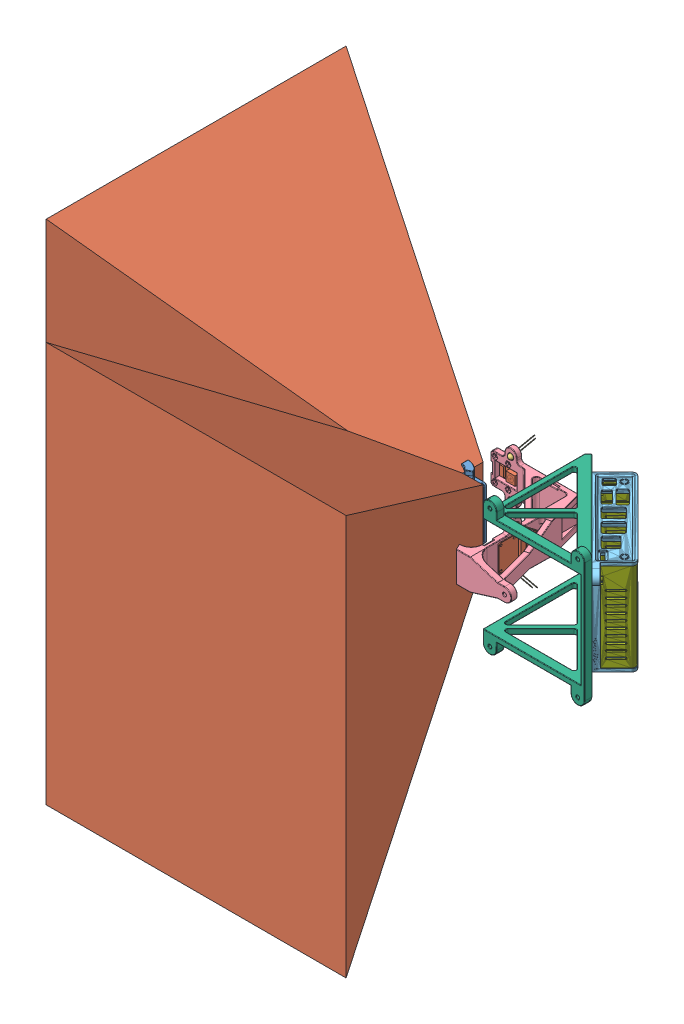
SolidWorks assembly Camera Mount Reference Assembly, configuration Default. Lengths in mm.
Overall size (267.17 129.73 171.67).
12 component instances, 7 part files, 32 mates.
Components (placement in the parent):
- Water Tunnel-1: Water Tunnel [Default] at origin size (93.6 95.16 58.74)
- Arducam IMX219AF-1: Arducam IMX219AF [Default] at (60.2 0 20.3) x (0 1 0) z (1 0 0) size (382.24 286.19 308.6)
- Arducam IMX219AF-2: Arducam IMX219AF [Default] at (-5.3 0 -45.2) x (0 -1 0) z (0 0 -1) size (382.24 286.19 308.6)
- 5mm White LED-1: 5mm White LED [Default] at (0 -19.4708 -46.6949) x (1 0 0) z (0 -0.978428 0.206589) size (5.4 26.8 5.4)
- 5mm White LED-2: 5mm White LED [Default] at (0 19.4708 -46.6949) x (1 0 0) z (0 -0.978428 -0.206589) size (5.4 26.8 5.4)
- 5mm White LED-3: 5mm White LED [Default] at (61.74 -19.5245 15) x (0 0 1) z (-0.22637 -0.974041 0) size (5.4 26.8 5.4)
- 5mm White LED-4: 5mm White LED [Default] at (61.74 19.5245 15) x (0 0 1) z (0.22637 -0.974041 0) size (5.4 26.8 5.4)
- Camera Mount-1: Camera Mount [Default] at (-5.3 0 -45.2) x (0 1 0) z (0 0 1) size (50.45 118.63 103.89)
- Jetson Mount Reference Assembly-1: Jetson Mount Reference Assembly [Default] at (34.246 111.7133 -83.3741) x (0.707107 0 0.707107) z (0.707107 0 -0.707107) size (136.69 127.15 104.23)
  - NanoBoxABSforB01_Bottom-1: NanoBoxABSforB01_Bottom [Default] at origin size (131.92 90.31 31)
  - Jetson Mount-1: Jetson Mount [Default] x (-1 0 0) z (0 0 -1) size (136.69 127.15 73.23)
  - NanoBoxABSforB01_Top-1: NanoBoxABSforB01_Top [Default] at (250 -0.2998 30.7) x (-1 0 0) z (0 0 -1) size (105.92 84.31 25)
Mates (geometry in assembly coordinates):
- Coincident1: coordinate: point of Water Tunnel-1
- Coincident2: coincident anti-aligned: plane of Water Tunnel-1 through (5 -15 20) normal (-1 0 0); plane of Arducam IMX219AF-1 through (5 0 20.3) normal (1 0 0)
- Coincident5: coincident aligned: plane of Water Tunnel-1 through (0 0 15) normal (0 0 1); plane of Arducam IMX219AF-1 through (60.2 0 15) normal (0 0 1)
- Coincident6: coincident aligned: plane of Water Tunnel-1 through (0 0 0) normal (0 1 0); plane of Arducam IMX219AF-1 through (60.2 0 20.3) normal (0 1 0)
- Coincident7: coincident: line of Water Tunnel-1 through (-5 -15 10) axis (0 1 0); plane of Arducam IMX219AF-2 through (-5.3 0 10) normal (0 0 -1)
- Coincident8: coincident: line of Water Tunnel-1 through (5 15 10) axis (0 -1 0); plane of Arducam IMX219AF-2 through (-5.3 0 10) normal (0 0 -1)
- Coincident9: coincident anti-aligned: plane of Water Tunnel-1 through (0 0 0) normal (1 0 0); plane of Arducam IMX219AF-2 through (0 0 -45.2) normal (-1 0 0)
- Coincident10: coincident anti-aligned: plane of Water Tunnel-1 through (0 0 0) normal (0 1 0); plane of Arducam IMX219AF-2 through (-5.3 0 -45.2) normal (0 -1 0)
- InPlace1: in place: plane of Arducam IMX219AF-2 through (-5.3 0 -45.2) normal (0 0 1); plane of ? through (0 0 -45.2) normal (0 0 1); moOrthogonalPlaneRef_w of Arducam IMX219AF-2 through (-5.3 0 -45.2) normal (0 0 1); plane of ? through (0 0 -45.2) normal (0 1 0); plane of Arducam IMX219AF-2 through (-5.3 0 -45.2) normal (0 0 1); plane of ? through (0 0 -45.2) normal (1 0 0); plane of Arducam IMX219AF-2 through (-5.3 0 -45.2) normal (0 0 1); unknown of Camera Mount-1
- Coincident11: coincident aligned: plane of Arducam IMX219AF-2; plane of Camera Mount-1
- Coincident12: coincident aligned: moOrthogonalPlaneRef_w of Arducam IMX219AF-2 through (-5.3 0 -45.2) normal (-1 0 0); plane of Camera Mount-1 through (-5.3 0 -45.2) normal (-1 0 0)
- Coincident13: coincident anti-aligned: moOrthogonalPlaneRef_w of Arducam IMX219AF-2 through (-5.3 0 -45.2) normal (0 -1 0); plane of Camera Mount-1 through (-5.3 0 -45.2) normal (0 1 0)
- Coincident14: coincident anti-aligned: plane of Arducam IMX219AF-2 through (0 0 -45.2) normal (-1 0 0); plane of 5mm White LED-1 through (0 -19.4708 -46.6949) normal (1 0 0)
- Coincident15: coincident anti-aligned: plane of Arducam IMX219AF-2 through (0 0 -45.2) normal (-1 0 0); plane of 5mm White LED-2 through (0 19.4708 -46.6949) normal (1 0 0)
- Coincident16: coincident aligned: plane of Arducam IMX219AF-1 through (60.2 0 15) normal (0 0 1); plane of 5mm White LED-3 through (61.74 -19.5245 15) normal (0 0 1)
- Coincident17: coincident aligned: plane of Arducam IMX219AF-1 through (60.2 0 15) normal (0 0 1); plane of 5mm White LED-4 through (61.74 19.5245 15) normal (0 0 1)
- Coincident20: coincident: line of assembly; point of Water Tunnel-1; line of 5mm White LED-1 through (0 18.4726 133.0094) axis (0 -0.206589 -0.978428)
- Coincident21: coincident: line of assembly; point of Water Tunnel-1; line of 5mm White LED-2 through (0 -18.4726 133.0094) axis (0 0.206589 -0.978428)
- Tangent4: tangent: line of Arducam IMX219AF-2 through (6.6 -16.6 -45.2) axis (-1 0 0); cylinder of 5mm White LED-1 through (0 -17.6528 -38.0847) axis (0 0.206589 0.978428) radius 2.5
- Tangent5: tangent: line of Arducam IMX219AF-2 through (6.6 16.6 -45.2) axis (-1 0 0); cylinder of 5mm White LED-2 through (0 17.6528 -38.0847) axis (0 -0.206589 0.978428) radius 2.5
- Tangent7: tangent: plane of Arducam IMX219AF-2 through (-5.3 0 -45.2) normal (0 0 1); circle of 5mm White LED-1
- Tangent8: tangent: plane of Arducam IMX219AF-2 through (-5.3 0 -45.2) normal (0 0 1); circle of 5mm White LED-2
- Coincident28: coincident: line of assembly; point of Water Tunnel-1; line of 5mm White LED-3 through (-117.1587 22.0521 15) axis (0.974041 -0.22637 0)
- Coincident29: coincident: line of assembly; point of Water Tunnel-1; line of 5mm White LED-4 through (-117.1587 -22.0521 15) axis (0.974041 0.22637 0)
- Tangent9: tangent: line of Arducam IMX219AF-1 through (60.2 -16.6 8.4) axis (0 0 1); cylinder of 5mm White LED-3 through (53.1684 -17.5325 15) axis (-0.974041 0.22637 0) radius 2.5
- Tangent10: tangent: line of Arducam IMX219AF-1 through (60.2 16.6 8.4) axis (0 0 1); cylinder of 5mm White LED-4 through (53.1684 17.5325 15) axis (-0.974041 -0.22637 0) radius 2.5
- Tangent11: tangent: plane of Arducam IMX219AF-1 through (60.2 0 20.3) normal (-1 0 0); circle of 5mm White LED-3
- Tangent12: tangent: plane of Arducam IMX219AF-1 through (60.2 0 20.3) normal (-1 0 0); circle of 5mm White LED-4
- Parallel2: parallel aligned: plane of Camera Mount-1 through (60.2 14.6 -42.2) normal (0 1 0); plane of Jetson Mount Reference Assembly-1/Jetson Mount-1 through (32.4783 57.7035 -81.6063) normal (0 1 0)
- Coincident30: coincident aligned: plane of Camera Mount-1 through (60.2 92.0065 58.6912) normal (0 0 1); plane of Jetson Mount Reference Assembly-1/Jetson Mount-1 through (34.246 111.7133 58.6912) normal (0 0 1)
- Distance1: distance = 10 mm: line of Jetson Mount Reference Assembly-1/Jetson Mount-1 through (72.4574 53.2035 -38.0916) axis (0 -1 0); plane of Camera Mount-1 through (55.8123 0 -61.575) normal (0.965926 0 -0.258819)
- Coincident33: coincident aligned: plane of Camera Mount-1 through (-5.3 0 -45.2) normal (0 1 0); plane of Jetson Mount Reference Assembly-1/NanoBoxABSforB01_Top-1 through (232.7309 0 71.6944) normal (0 1 0)
